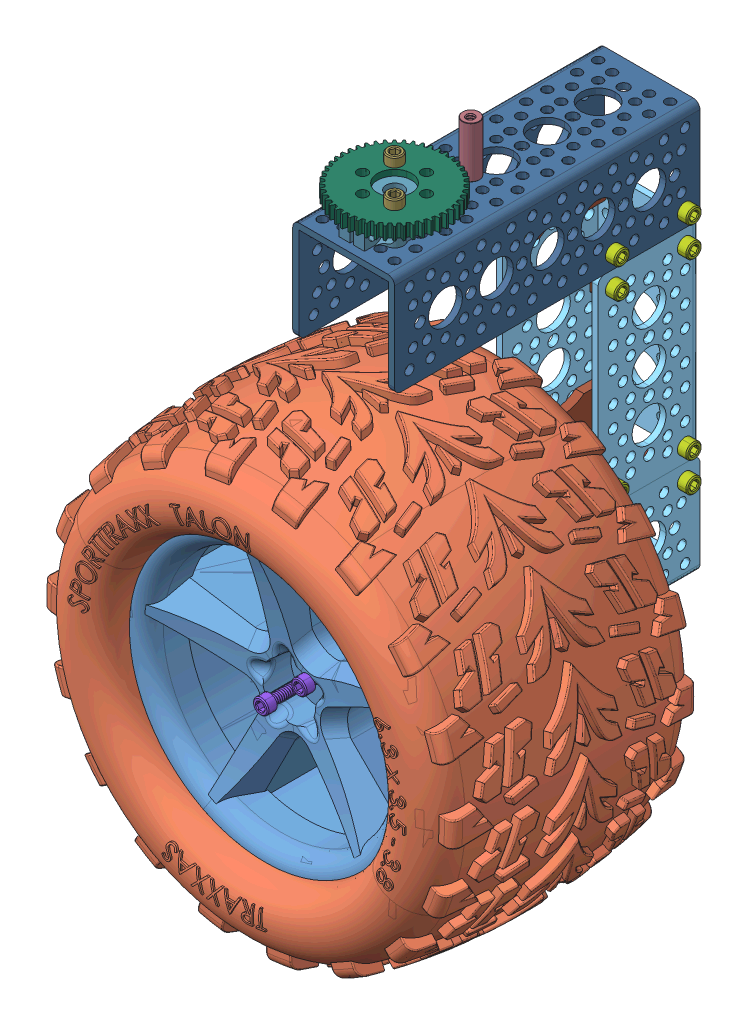
SolidWorks assembly Corner Wheel Assembly, configuration Default. Lengths in mm.
Overall size (220.06 262.43 155.76).
50 component instances, 15 part files, 0 mates.
Components (placement in the parent):
- Corner Wheel Assembly.STEP-1: Corner Wheel Assembly.STEP [Default] at origin size (220.06 262.43 155.76)
  - Wheel Assembly_Middle Wheel.STEP-1: Wheel Assembly_Middle Wheel.STEP [Default] at (53.3657 55.989 87.6081) size (220.06 220.05 155.02)
    - Wheel.STEP-1: Wheel.STEP [Default] at (-96.6519 -10.9387 140.7011) x (0 0 1) z (0.454033 0.890985 0) size (101.31 163.62 163.59)
      - Wheel Rim.STEP-1: Wheel Rim.STEP [Default] at (-5.7009 62.13 94.8184) size (88.37 101.61 101.61)
      - Wheel Tire.STEP-1: Wheel Tire.STEP [Default] at (-5.7009 62.1295 94.8183) size (101.31 163.62 163.59)
    - 25m Bore Side Tapped Clamping Mount.STEP-1: 25m Bore Side Tapped Clamping Mount.STEP [Default] at (1.1407 51.5007 106.1447) x (1 0 0) z (0 -1 0) size (33.53 7.62 39.78)
      - 25m Bore Side Tapped Clamping Mount-0.STEP-1: 25m Bore Side Tapped Clamping Mount-0.STEP [Default] at (0.615 -8.6446 6.1668) size (33.53 7.62 39.7)
      - #6-32 0_5 Bolt.STEP-1: #6-32 0_5 Bolt.STEP [Default] at (-31.135 -4.8346 -13.2719) x (0 0.2706 0.962692) z (-1 0 0) size (6 6 16.43)
    - 3 Aluminum Channel.STEP-1: 3 Aluminum Channel.STEP [Default] at (-17.2943 26.284 30.6898) size (38.1 38.1 76.2)
    - 25mm Motor and Encoder.STEP-1: 25mm Motor and Encoder.STEP [Default] at (-28.8188 49.6309 104.1252) x (0.990268 -0.139173 0) z (0 0 1) size (25 32.85 80)
    - 6-32_SHCS_6-32 SHCS X .250.STEP-1: 6-32_SHCS_6-32 SHCS X .250.STEP [Default] at (14.4557 58.8044 101.3102) x (0 0 -1) z (1 0 0) size (10.11 10.22 13.01)
    - 6-32_SHCS_6-32 SHCS X .250.STEP-2: 6-32_SHCS_6-32 SHCS X .250.STEP [Default] at (-10.9443 58.8044 101.3102) x (0 0.924225 0.381849) z (-1 0 0) size (10.11 10.22 13.01)
    - 6-32_SHCS_6-32 SHCS X .250.STEP-3: 6-32_SHCS_6-32 SHCS X .250.STEP [Default] at (-10.9443 31.8636 101.3102) x (0 0.924225 0.381849) z (-1 0 0) size (10.11 10.22 13.01)
    - 6-32_SHCS_6-32 SHCS X .250.STEP-4: 6-32_SHCS_6-32 SHCS X .250.STEP [Default] at (14.4557 31.8636 101.3102) x (0 0 -1) z (1 0 0) size (10.11 10.22 13.01)
    - 6-32_SHCS_6-32 SHCS X 1.250.STEP-1: 6-32_SHCS_6-32 SHCS X 1.250.STEP [Default] at (8.8978 52.0137 133.797) x (-0.454033 -0.890985 0) z (0 0 1) size (10.11 10.22 38.41)
    - 6-32_SHCS_6-32 SHCS X 1.250.STEP-2: 6-32_SHCS_6-32 SHCS X 1.250.STEP [Default] at (-5.3865 38.6543 133.797) x (-0.454033 -0.890985 0) z (0 0 1) size (10.11 10.22 38.41)
    - 4mm Face Tapped Clamping Hub.STEP-1: 4mm Face Tapped Clamping Hub.STEP [Default] at (1.7557 45.334 125.4752) x (0.999441 -0.033438 0) z (-0.033438 -0.999441 0) size (20.57 9.53 26.29)
  - Wheel.STEP-1: Wheel.STEP [Default] at (-43.2862 45.0503 228.3093) x (0 0 1) z (0.454033 0.890985 0) size (101.31 163.62 163.59)
    - Wheel Rim.STEP-1: Wheel Rim.STEP [Default] at (-5.7009 62.13 94.8184) size (88.37 101.61 101.61)
    - Wheel Tire.STEP-1: Wheel Tire.STEP [Default] at (-5.7009 62.1295 94.8183) size (101.31 163.62 163.59)
  - 3 Aluminum Channel.STEP-1: 3 Aluminum Channel.STEP [Default] at (36.0714 196.573 118.2979) x (1 0 0) z (0 -1 0) size (38.1 38.1 76.2)
  - 4.5 Aluminum channel.STEP-1: 4.5 Aluminum channel.STEP [Default] at (36.0714 234.673 232.5979) x (1 0 0) z (0 0 -1) size (38.1 38.1 114.3)
  - Channel Connector.STEP-1: Channel Connector.STEP [Default] at (71.8854 120.373 137.3479) x (0 0 1) z (0 -1 0) size (33.29 3.18 17.51)
  - Channel Connector.STEP-2: Channel Connector.STEP [Default] at (41.5324 120.373 137.3479) x (0 0 1) z (0 -1 0) size (33.29 3.18 17.51)
  - Channel Connector.STEP-3: Channel Connector.STEP [Default] at (71.8854 196.573 137.3479) x (0 0 1) z (0 -1 0) size (33.29 3.18 17.51)
  - Channel Connector.STEP-4: Channel Connector.STEP [Default] at (38.3574 196.573 137.3479) x (0 0 1) z (0 1 0) size (33.29 3.18 17.51)
  - 6-32_SHCS_6-32 SHCS X .250.STEP-1: 6-32_SHCS_6-32 SHCS X .250.STEP [Default] at (42.4214 114.7934 150.8183) x (0 0.924225 0.381849) z (-1 0 0) size (10.11 10.22 13.01)
  - 6-32_SHCS_6-32 SHCS X .250.STEP-2: 6-32_SHCS_6-32 SHCS X .250.STEP [Default] at (67.8214 114.7934 150.8183) x (0 0 -1) z (1 0 0) size (10.11 10.22 13.01)
  - 6-32_SHCS_6-32 SHCS X .250.STEP-3: 6-32_SHCS_6-32 SHCS X .250.STEP [Default] at (42.4214 114.7934 123.8776) x (0 0.924225 0.381849) z (-1 0 0) size (10.11 10.22 13.01)
  - 6-32_SHCS_6-32 SHCS X .250.STEP-4: 6-32_SHCS_6-32 SHCS X .250.STEP [Default] at (67.8214 114.7934 123.8776) x (0 0 -1) z (1 0 0) size (10.11 10.22 13.01)
  - 6-32_SHCS_6-32 SHCS X .250.STEP-5: 6-32_SHCS_6-32 SHCS X .250.STEP [Default] at (67.8214 125.9526 123.8776) x (0 -0.924225 -0.381849) z (1 0 0) size (10.11 10.22 13.01)
  - 6-32_SHCS_6-32 SHCS X .250.STEP-6: 6-32_SHCS_6-32 SHCS X .250.STEP [Default] at (42.4214 125.9526 123.8776) x (0 0 1) z (-1 0 0) size (10.11 10.22 13.01)
  - 6-32_SHCS_6-32 SHCS X .250.STEP-7: 6-32_SHCS_6-32 SHCS X .250.STEP [Default] at (42.4214 125.9526 150.8183) x (0 0.924225 0.381849) z (-1 0 0) size (10.11 10.22 13.01)
  - 6-32_SHCS_6-32 SHCS X .250.STEP-8: 6-32_SHCS_6-32 SHCS X .250.STEP [Default] at (67.8214 125.9526 150.8183) x (0 0 -1) z (1 0 0) size (10.11 10.22 13.01)
  - 6-32_SHCS_6-32 SHCS X .250.STEP-9: 6-32_SHCS_6-32 SHCS X .250.STEP [Default] at (42.4214 190.9934 150.8183) x (0 0.924225 0.381849) z (-1 0 0) size (10.11 10.22 13.01)
  - 6-32_SHCS_6-32 SHCS X .250.STEP-10: 6-32_SHCS_6-32 SHCS X .250.STEP [Default] at (67.8214 190.9934 150.8183) x (0 0 -1) z (1 0 0) size (10.11 10.22 13.01)
  - 6-32_SHCS_6-32 SHCS X .250.STEP-11: 6-32_SHCS_6-32 SHCS X .250.STEP [Default] at (42.4214 190.9934 123.8776) x (0 0.924225 0.381849) z (-1 0 0) size (10.11 10.22 13.01)
  - 6-32_SHCS_6-32 SHCS X .250.STEP-12: 6-32_SHCS_6-32 SHCS X .250.STEP [Default] at (67.8214 190.9934 123.8776) x (0 0 -1) z (1 0 0) size (10.11 10.22 13.01)
  - 6-32_SHCS_6-32 SHCS X .250.STEP-13: 6-32_SHCS_6-32 SHCS X .250.STEP [Default] at (42.4214 202.1526 150.8183) x (0 0.924225 0.381849) z (-1 0 0) size (10.11 10.22 13.01)
  - 6-32_SHCS_6-32 SHCS X .250.STEP-14: 6-32_SHCS_6-32 SHCS X .250.STEP [Default] at (67.8214 202.1526 150.8183) x (0 0 -1) z (1 0 0) size (10.11 10.22 13.01)
  - 6-32_SHCS_6-32 SHCS X .250.STEP-15: 6-32_SHCS_6-32 SHCS X .250.STEP [Default] at (42.4214 202.1526 123.8776) x (0 0.924225 0.381849) z (-1 0 0) size (10.11 10.22 13.01)
  - 6-32_SHCS_6-32 SHCS X .250.STEP-16: 6-32_SHCS_6-32 SHCS X .250.STEP [Default] at (67.8214 202.1526 123.8776) x (0 0 -1) z (1 0 0) size (10.11 10.22 13.01)
  - 6-32_SHCS_6-32 SHCS X .375.STEP-1: 6-32_SHCS_6-32 SHCS X .375.STEP [Default] at (62.0362 236.8955 220.4627) x (1 0 0) z (0 1 0) size (10.11 10.22 16.18)
  - 6-32_SHCS_6-32 SHCS X .375.STEP-2: 6-32_SHCS_6-32 SHCS X .375.STEP [Default] at (48.2066 241.912 220.4627) x (0.296364 0 -0.955075) z (0 -1 0) size (10.11 10.22 16.18)
  - 6-32_SHCS_6-32 SHCS X .375.STEP-3: 6-32_SHCS_6-32 SHCS X .375.STEP [Default] at (62.0362 241.912 206.6331) x (-0.850964 0 -0.525225) z (0 -1 0) size (10.11 10.22 16.18)
  - 6-32_SHCS_6-32 SHCS X .375.STEP-4: 6-32_SHCS_6-32 SHCS X .375.STEP [Default] at (48.2066 236.8955 206.6331) x (-0.379425 0 0.925222) z (0 1 0) size (10.11 10.22 16.18)
  - 6-32_SHCS_6-32 SHCS X .375.STEP-5: 6-32_SHCS_6-32 SHCS X .375.STEP [Default] at (55.1214 241.912 184.9729) x (-0.837169 0 -0.546944) z (0 -1 0) size (10.11 10.22 16.18)
  - 6_32 standoff.STEP-1: 6_32 standoff.STEP [Default] at (55.1214 234.673 184.9729) x (0.654773 0 0.755826) z (-0.755826 0 0.654773) size (6.34 19.06 6.34)
  - 0.25 Face Tapped Clamping Hub.STEP-1: 0.25 Face Tapped Clamping Hub.STEP [Default] at (55.1214 244.198 213.5479) x (1 0 0) z (0 0 -1) size (20.57 9.53 26.29)
  - 48 Tooth 32 Pitch Gear.STEP-1: 48 Tooth 32 Pitch Gear.STEP [Default] at (55.1214 241.658 213.5479) x (0.965926 0 -0.258819) z (0.258819 0 0.965926) size (39.7 4.76 39.7)
